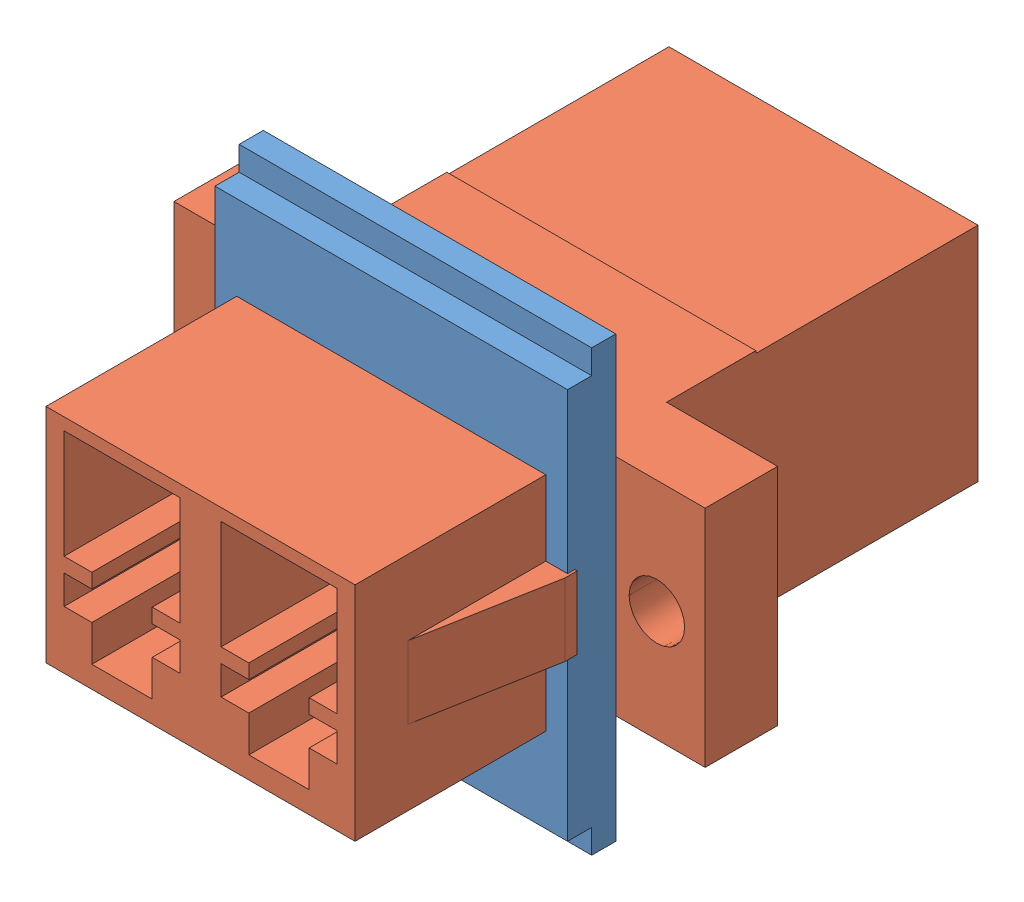
SolidWorks assembly Keystone-LC, configuration Standard. Lengths in mm.
Overall size (22 18.2 25.8).
2 component instances, 2 part files, 6 mates.
Components (placement in the parent):
- Keystone-LC-Pannel-1: Keystone-LC-Pannel [Standard] at (-14.6 -17.2 0) x (-1 0 0) z (0 0 -1) size (14.6 18.2 2)
- CONN-LC-TYPE-SCREW-1: CONN-LC-TYPE-SCREW [Standard] at (-7.3 -13.7 7.9) size (22 9.3 25.8)
Mates (geometry in assembly coordinates):
- Deckungsgleich1: coincident aligned: plane of Keystone-LC-Pannel-1 through (-14.6 -17.2 0) normal (0 0 1); plane of assembly through (0 0 0) normal (0 0 1)
- Deckungsgleich2: coincident aligned: plane of Keystone-LC-Pannel-1 through (0 -17.2 -1) normal (1 0 0); plane of assembly through (0 0 0) normal (1 0 0)
- Deckungsgleich3: coincident aligned: plane of Keystone-LC-Pannel-1 through (0 0 -2) normal (0 1 0); plane of assembly through (0 0 0) normal (0 1 0)
- Deckungsgleich4: coincident: plane of Keystone-LC-Pannel-1 through (-13.7 -4.5 -10) normal (0 -1 0); plane of CONN-LC-TYPE-SCREW-1 through (-7.3 -4.5 7.9) normal (0 1 0)
- Deckungsgleich5: coincident: plane of Keystone-LC-Pannel-1 through (-0.9 -4.5 -10) normal (-1 0 0); plane of CONN-LC-TYPE-SCREW-1 through (-0.9 -13.7 7.9) normal (1 0 0)
- Deckungsgleich6: coincident anti-aligned: plane of Keystone-LC-Pannel-1 through (-14.6 -17.2 -2) normal (0 0 -1); plane of CONN-LC-TYPE-SCREW-1 through (-7.3 -13.7 -2) normal (0 0 1)
